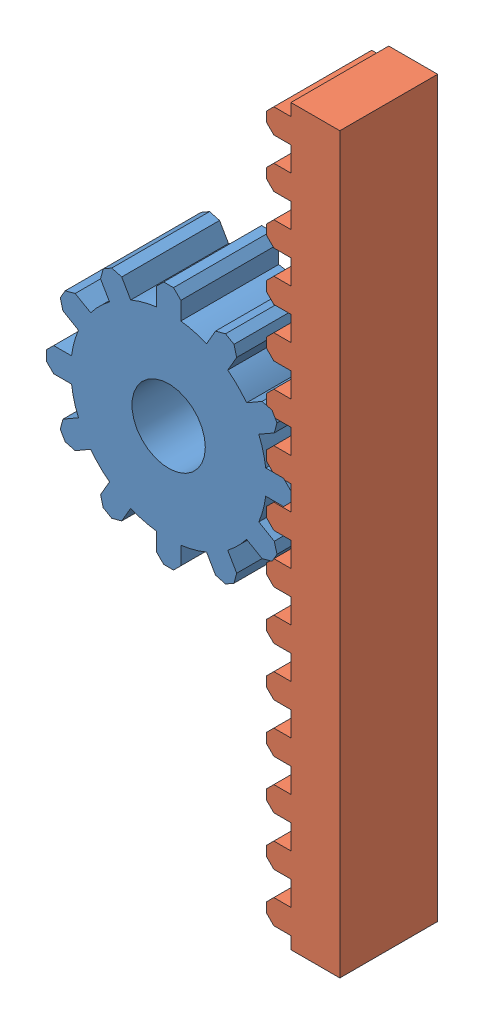
SolidWorks assembly Assem1, configuration Default. Lengths in mm.
Overall size (304.8 762 101.6).
2 component instances, 2 part files, 2 mates.
Components (placement in the parent):
- pinon-1: pinon [Default] at (-81.2766 -223.3382 67.7027) size (254 254 101.6)
- rack-1: rack [Default] at (71.1234 -249.8572 67.7027) x (0 1 0) z (0 0 1) size (762 76.16 101.6)
Mates (geometry in assembly coordinates):
- Coincident1: coincident aligned: plane of pinon-1 through (-120.546 268.669 67.239) normal (0 0 1); plane of rack-1 through (31.854 -249.8572 67.239) normal (0 0 1)
- Coincident3: coincident anti-aligned: plane of pinon-1 through (6.454 255.969 -34.361) normal (1 0 0); plane of rack-1 through (6.454 131.1428 67.239) normal (-1 0 0)
